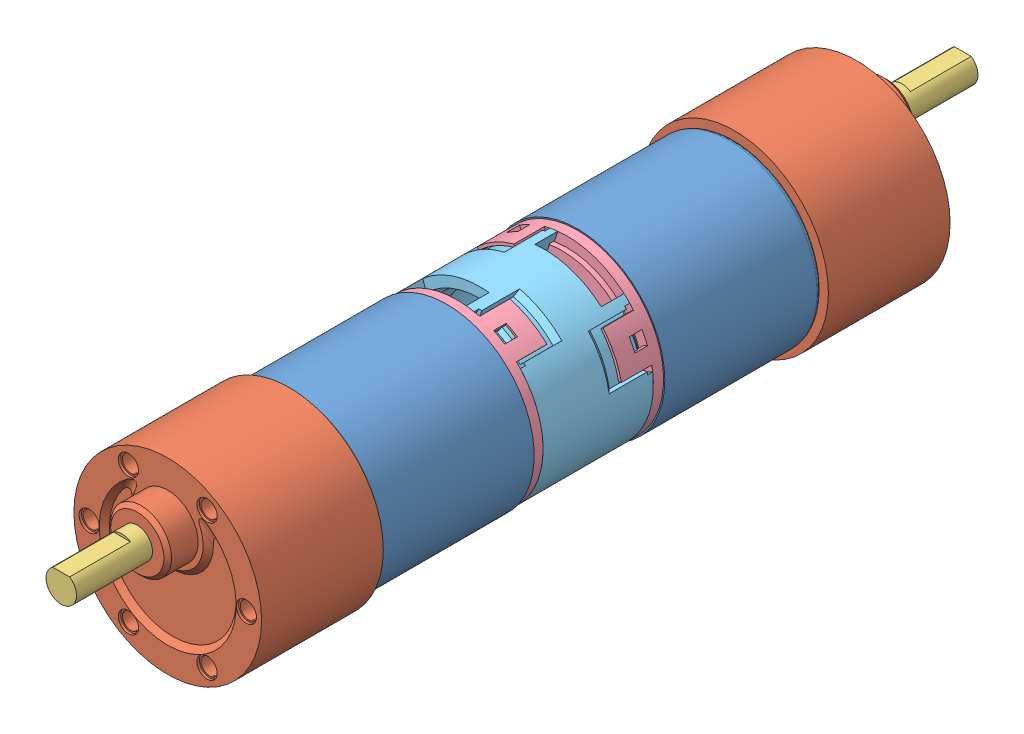
SolidWorks assembly Motor_Couple_ASM_rev0, configuration Default. Lengths in mm.
Overall size (42.65 42.65 177.75).
11 component instances, 5 part files, 6 mates.
Components (placement in the parent):
- Motor_ASM_rev1-1: Motor_ASM_rev1 [Default] at (3.3139 25.8281 28.4781) size (42.65 42.65 84)
  - Motor_rev0-1: Motor_rev0 [Default] at (12.0471 18.5029 10.1025) size (34.5 34.5 31)
  - Gearbox_rev0-1: Gearbox_rev0 [Default] at (12.0471 18.5029 41.1025) size (37 37 30)
  - Shaft_rev0-1: Shaft_rev0 [Default] at (12.0471 25.5029 65.1025) size (6 6 21)
  - Back_Motor_Cover_rev0-1: Back_Motor_Cover_rev0 [Default] at (12.0471 18.5029 10.1025) x (0.953717 0.300706 0) z (0 0 -1) size (34 34 8)
- Encoder_Cap_rev1-1-1: Encoder_Cap_rev1-1 [Default] at (15.361 44.331 14.8305) x (-0.953717 0.300706 0) z (0 0 1) size (34 34 21.75)
- Motor_ASM_rev1-2: Motor_ASM_rev1 [Default] at (27.4081 25.8281 22.933) x (-1 0 0) z (0 0 -1) size (42.65 42.65 84)
  - Motor_rev0-1: Motor_rev0 [Default] at (12.0471 18.5029 10.1025) size (34.5 34.5 31)
  - Gearbox_rev0-1: Gearbox_rev0 [Default] at (12.0471 18.5029 41.1025) size (37 37 30)
  - Shaft_rev0-1: Shaft_rev0 [Default] at (12.0471 25.5029 65.1025) size (6 6 21)
  - Back_Motor_Cover_rev0-1: Back_Motor_Cover_rev0 [Default] at (12.0471 18.5029 10.1025) x (0.953717 0.300706 0) z (0 0 -1) size (34 34 8)
Mates (geometry in assembly coordinates):
- Coincident2: coincident: plane of Motor_ASM_rev1-1/Back_Motor_Cover_rev0-1 through (15.361 44.331 36.5805) normal (0 0 -1); plane of Encoder_Cap_rev1-1-1 through (15.361 44.331 36.5805) normal (0 0 1)
- Concentric1: concentric: cylinder of Motor_ASM_rev1-1/Back_Motor_Cover_rev0-1 through (15.361 44.331 30.5805) axis (0 0 1) radius 16.25; cylinder of Encoder_Cap_rev1-1-1 through (15.361 44.331 28.0805) axis (0 0 1) radius 16
- Coincident3: coincident aligned: plane of Motor_ASM_rev1-1/Back_Motor_Cover_rev0-1 through (15.361 44.331 38.5805) normal (0.953717 0.300706 0); plane of Encoder_Cap_rev1-1-1 through (15.361 44.331 14.8305) normal (0.953717 0.300706 0)
- Coincident4: coincident: plane of Encoder_Cap_rev1-1-1 through (15.361 44.331 14.8305) normal (0 0 -1); plane of Motor_ASM_rev1-2/Back_Motor_Cover_rev0-1 through (15.361 44.331 14.8305) normal (0 0 1)
- Concentric2: concentric: cylinder of Encoder_Cap_rev1-1-1 through (15.361 44.331 23.3305) axis (0 0 -1) radius 16; cylinder of Motor_ASM_rev1-2/Back_Motor_Cover_rev0-1 through (15.361 44.331 20.8305) axis (0 0 -1) radius 16.25
- Coincident5: coincident aligned: plane of Encoder_Cap_rev1-1-1 through (15.361 44.331 14.8305) normal (-0.953717 0.300706 0); plane of Motor_ASM_rev1-2/Back_Motor_Cover_rev0-1 through (15.361 44.331 12.8305) normal (-0.953717 0.300706 0)
